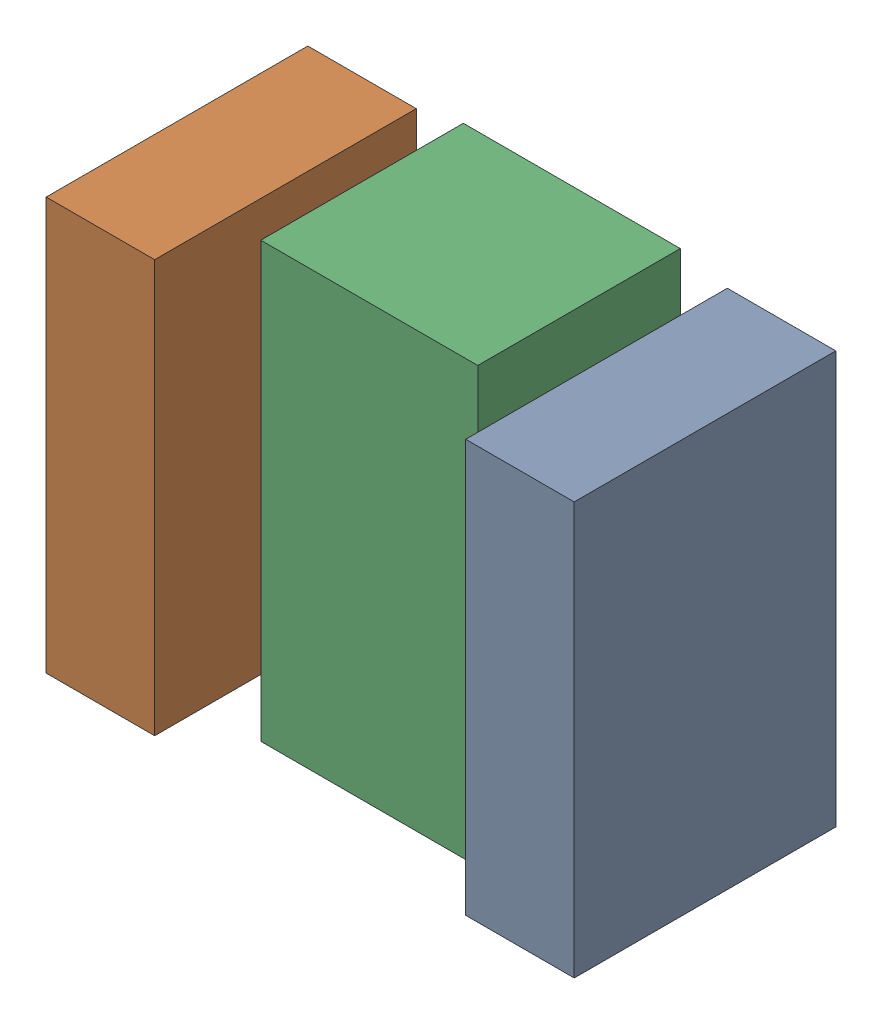
SolidWorks assembly C11_Motor_2Kanaloa_v2.0.0_Motor, configuration Default. Lengths in mm.
Overall size (3.65 3 1.81).
6 component instances, 2 part files, 0 mates.
Components (placement in the parent):
- 334788400-1: 334788400 [Default] at (121.544 53.086 0) size (0.75 2.85 1.81)
  - Extruded_5-1: Extruded_5 [Default] at origin size (0.75 2.85 1.81)
- 334788400-2: 334788400 [Default] at (118.644 53.086 0) size (0.75 2.85 1.81)
  - Extruded_5-1: Extruded_5 [Default] at origin size (0.75 2.85 1.81)
- 334788656-1: 334788656 [Default] at (120.094 53.086 0) size (1.5 3 1.4)
  - Extruded_1-1: Extruded_1 [Default] at origin size (1.5 3 1.4)
